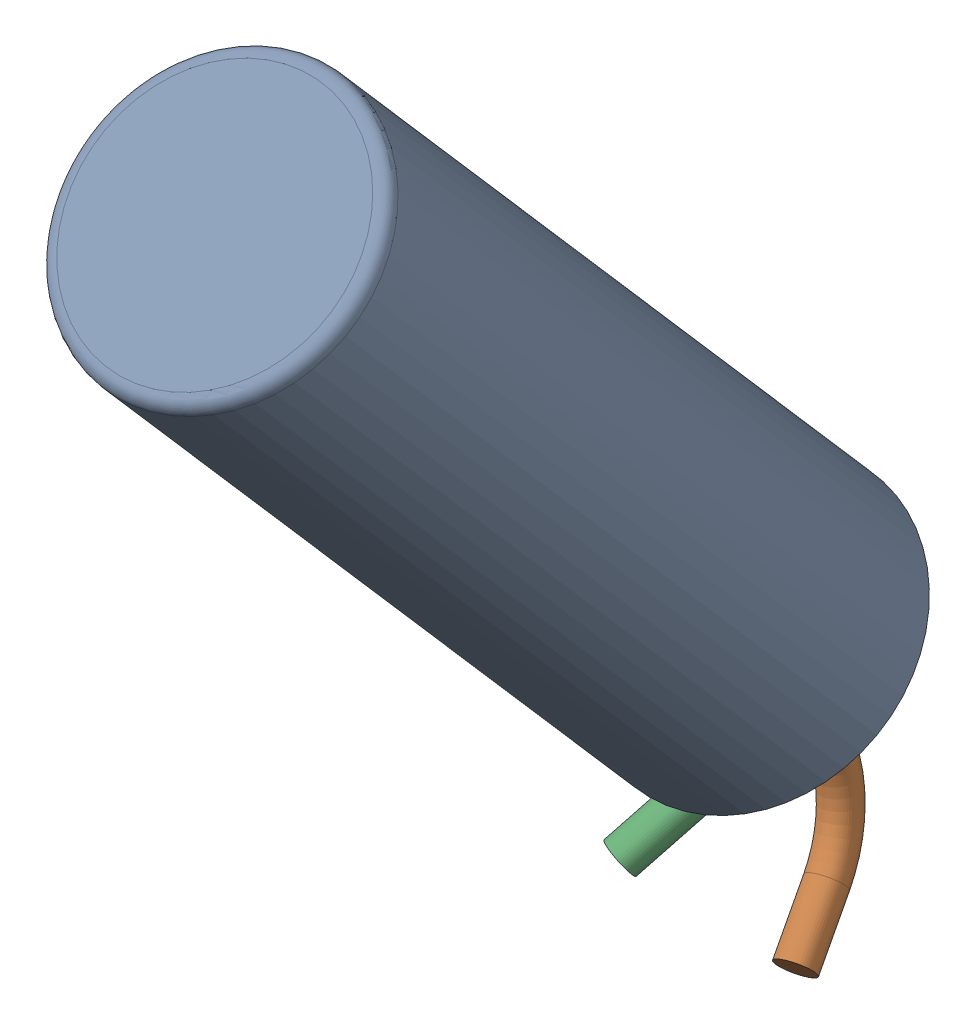
SolidWorks assembly XTAL-XYL_SMD, configuration 默认. Lengths in mm.
Overall size (2.1 7.22 5.65).
4 component instances, 2 part files, 0 mates.
Components (placement in the parent):
- XTAL-XYL-1: XTAL-XYL [默认] at (0.0959 -0.4998 -2.6168) x (0 -0.656059 0.75471) z (0 0.75471 0.656059) size (2.1 2.1 6.2)
  - User_Library-R38_100mils_Fillet-1: User_Library-R38_100mils_Fillet [默认] at origin size (2.1 2.1 6.2)
- 零件1-1: 零件1 [默认] at (0.7193 -1.5563 -0.0297) x (0.965926 0.169801 -0.195333) z (-0.258819 0.633704 -0.728993) size (0.26 1.23 1.33)
- 零件1-2: 零件1 [默认] at (-0.6339 -1.5286 -0.0615) x (0.939693 -0.224385 0.258126) z (0.34202 0.616494 -0.709195) size (0.26 1.23 1.33)
